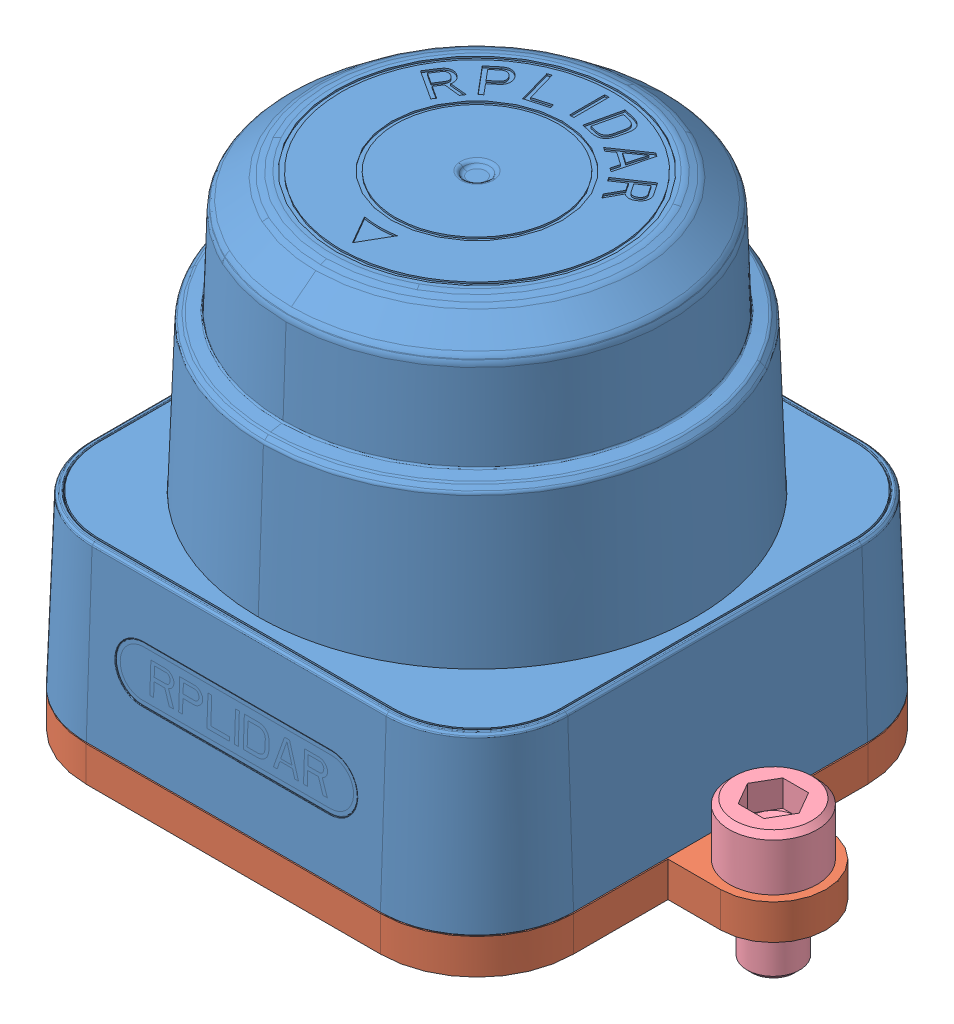
SolidWorks assembly rplidar, configuration Default. Lengths in mm.
Overall size (97.23 61.01 108.71).
8 component instances, 4 part files, 16 mates.
Components (placement in the parent):
- rplidar-s1-1: rplidar-s1 [Default] x (1 0 0) z (0 -1 0) size (97.23 108.71 51.5)
- rplidar-mount-1: rplidar-mount [Default] x (-1 0 0) z (0 1 0) size (79.49 55.49 4)
- bolt-countersunk-M2.5-1: bolt-countersunk-M2.5 [Default] at (21.5 -4 21.5) x (0 1 0) z (0 0 1) size (8 5 5)
- bolt-countersunk-M2.5-2: bolt-countersunk-M2.5 [Default] at (21.5 -4 -21.5) x (0 1 0) z (0.188455 0 0.982082) size (8 5 5)
- bolt-countersunk-M2.5-3: bolt-countersunk-M2.5 [Default] at (-21.5 -4 -21.5) x (0 1 0) z (0.395734 0 0.918365) size (8 5 5)
- bolt-countersunk-M2.5-4: bolt-countersunk-M2.5 [Default] at (-21.5 -4 21.5) x (0 1 0) z (0.6 0 0.8) size (8 5 5)
- socket head cap screw_am-1: socket head cap screw_am [B18.3.1M - 6 x 1.0 x 10 Hex SHCS -- 10NHX] at (33.7449 6 0) x (0 -1 0) z (0 0 1) size (16 10 10)
- socket head cap screw_am-2: socket head cap screw_am [B18.3.1M - 6 x 1.0 x 10 Hex SHCS -- 10NHX] at (-33.7449 6 0) x (0 -1 0) z (0 0 1) size (16 10 10)
Mates (geometry in assembly coordinates):
- InPlace1: in place: plane of rplidar-s1-1 through (0 0 0) normal (0 1 0); plane of ? through (0 0 0) normal (0 1 0); moOrthogonalPlaneRef_w of rplidar-s1-1 through (0 0 0) normal (0 1 0); plane of ? through (0 0 0) normal (0 0 -1); plane of rplidar-s1-1 through (0 0 0) normal (0 1 0); plane of ? through (0 0 0) normal (1 0 0); plane of rplidar-s1-1 through (0 0 0) normal (0 1 0); unknown of rplidar-mount-1
- Coincident1: coincident aligned: plane of rplidar-s1-1; plane of rplidar-mount-1
- Coincident2: coincident aligned: moOrthogonalPlaneRef_w of rplidar-s1-1 through (0 0 0) normal (0 0 1); plane of rplidar-mount-1 through (0 0 0) normal (0 0 1)
- Coincident3: coincident anti-aligned: moOrthogonalPlaneRef_w of rplidar-s1-1 through (0 0 0) normal (1 0 0); plane of rplidar-mount-1 through (0 0 0) normal (-1 0 0)
- Concentric1: concentric anti-aligned: cylinder of rplidar-mount-1 through (21.5 -4 21.5) axis (0 1 0) radius 1.35; cylinder of bolt-countersunk-M2.5-1 through (21.5 -6.2818 21.5) axis (0 -1 0) radius 1.25
- Coincident5: coincident aligned: plane of rplidar-mount-1 through (0 -4 0) normal (0 -1 0); plane of bolt-countersunk-M2.5-1 through (21.5 -4 21.5) normal (0 -1 0)
- Coincident6: coincident aligned: plane of rplidar-mount-1 through (0 -4 0) normal (0 -1 0); plane of bolt-countersunk-M2.5-2 through (21.5 -4 -21.5) normal (0 -1 0)
- Concentric2: concentric anti-aligned: cylinder of rplidar-mount-1 through (21.5 -4 -21.5) axis (0 1 0) radius 1.35; cylinder of bolt-countersunk-M2.5-2 through (21.5 -6.2818 -21.5) axis (0 -1 0) radius 1.25
- Coincident7: coincident aligned: plane of rplidar-mount-1 through (0 -4 0) normal (0 -1 0); plane of bolt-countersunk-M2.5-3 through (-21.5 -4 -21.5) normal (0 -1 0)
- Concentric3: concentric anti-aligned: cylinder of rplidar-mount-1 through (-21.5 -4 -21.5) axis (0 1 0) radius 1.35; cylinder of bolt-countersunk-M2.5-3 through (-21.5 -6.2818 -21.5) axis (0 -1 0) radius 1.25
- Coincident8: coincident aligned: plane of rplidar-mount-1 through (0 -4 0) normal (0 -1 0); plane of bolt-countersunk-M2.5-4 through (-21.5 -4 21.5) normal (0 -1 0)
- Concentric4: concentric anti-aligned: cylinder of rplidar-mount-1 through (-21.5 -4 21.5) axis (0 1 0) radius 1.35; cylinder of bolt-countersunk-M2.5-4 through (-21.5 -6.2818 21.5) axis (0 -1 0) radius 1.25
- Concentric5: concentric aligned: cylinder of rplidar-mount-1 through (33.7449 -4 0) axis (0 1 0) radius 3.1; cylinder of socket head cap screw_am-1 through (33.7449 37.75 0) axis (0 1 0) radius 5
- Coincident10: coincident anti-aligned: plane of rplidar-mount-1 through (0 0 0) normal (0 1 0); plane of socket head cap screw_am-1 through (38.7449 0 0) normal (0 -1 0)
- Concentric6: concentric aligned: cylinder of rplidar-mount-1 through (-33.7449 -4 0) axis (0 1 0) radius 3.1; cylinder of socket head cap screw_am-2 through (-33.7449 37.75 0) axis (0 1 0) radius 5
- Coincident11: coincident anti-aligned: plane of rplidar-mount-1 through (0 0 0) normal (0 1 0); plane of socket head cap screw_am-2 through (-28.7449 0 0) normal (0 -1 0)
